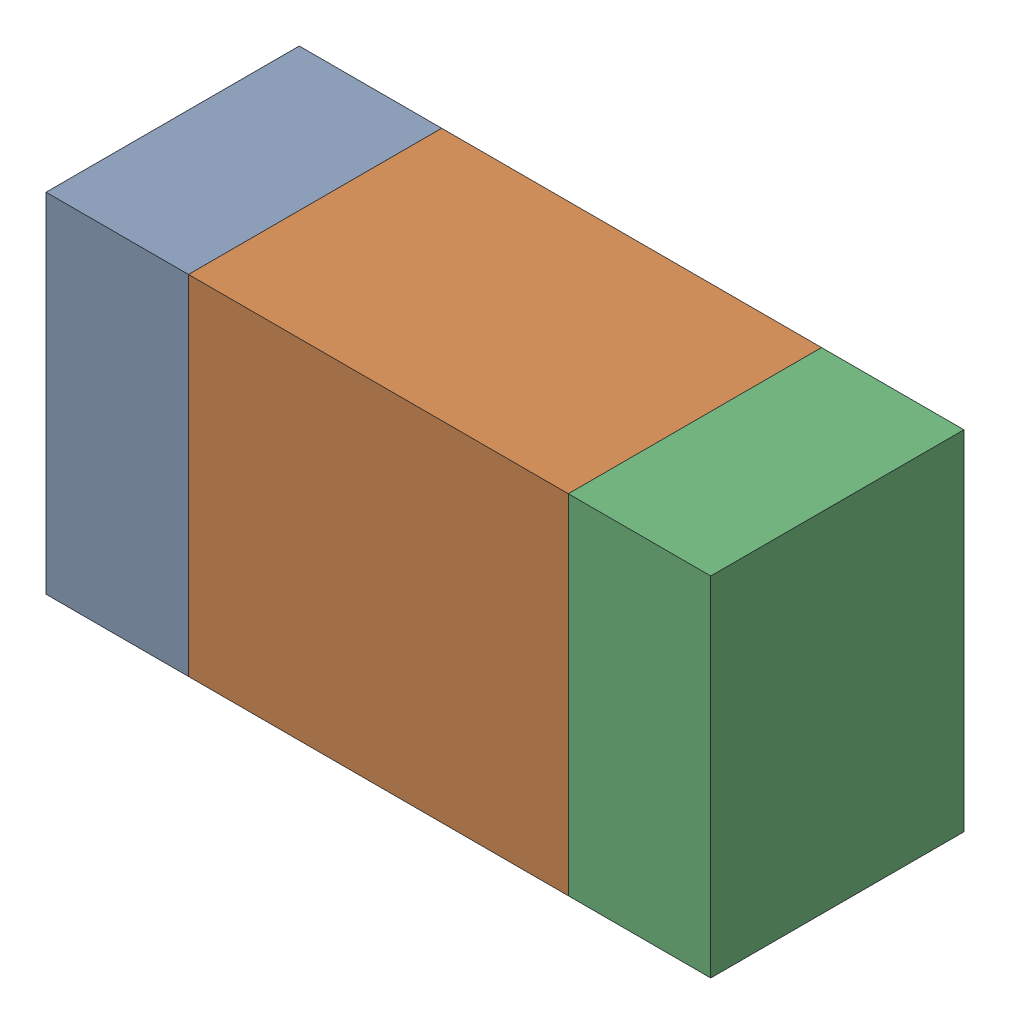
SolidWorks assembly R502_1PCB, configuration Default. Lengths in mm.
Overall size (1.05 0.55 0.4).
6 component instances, 2 part files, 0 mates.
Components (placement in the parent):
- 854785432-1: 854785432 [Default] at (151.7376 121.2501 0) size (0.22 0.55 0.4)
  - Extruded-1: Extruded [Default] at origin size (0.22 0.55 0.4)
- 854785568-1: 854785568 [Default] at (152.1501 121.2501 0) size (0.6 0.55 0.4)
  - Extruded_2-1: Extruded_2 [Default] at origin size (0.6 0.55 0.4)
- 854785432-2: 854785432 [Default] at (152.5626 121.2501 0) size (0.22 0.55 0.4)
  - Extruded-1: Extruded [Default] at origin size (0.22 0.55 0.4)
